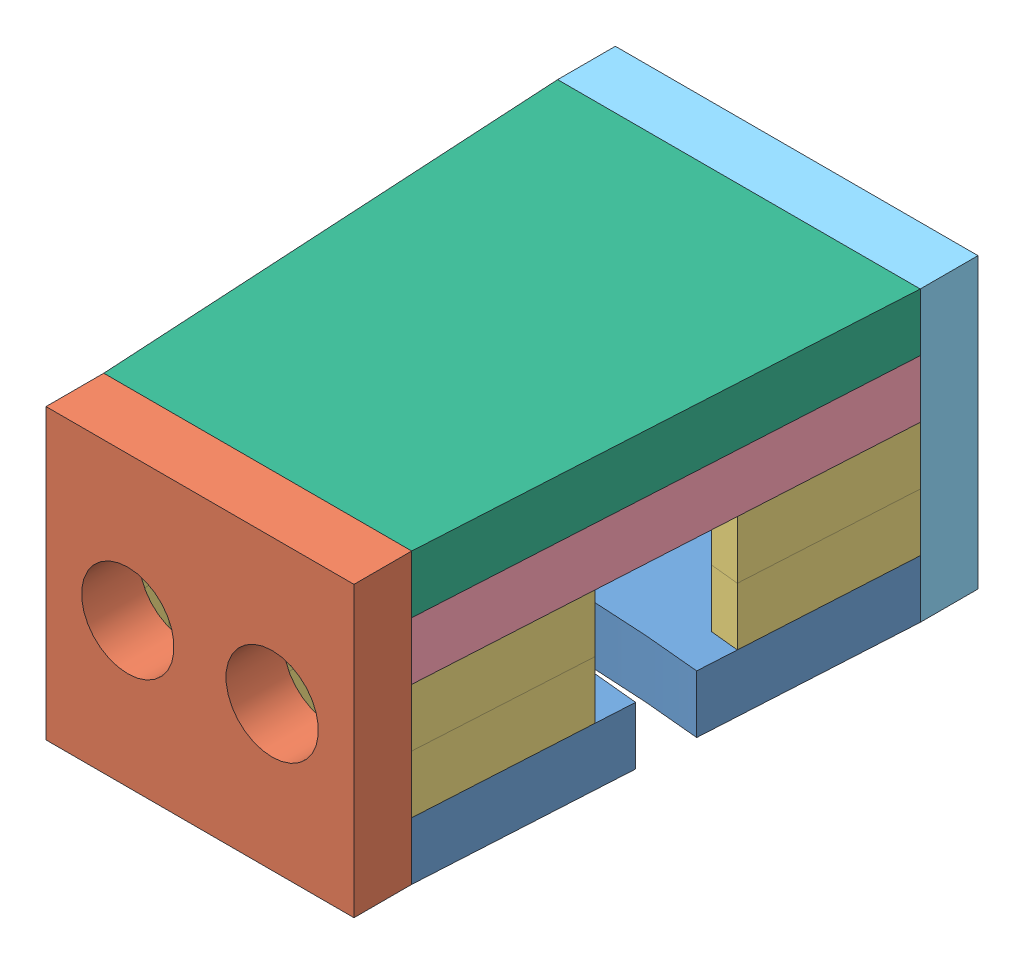
SolidWorks assembly housing, configuration Default. Lengths in mm.
Overall size (18.84 15 31).
7 component instances, 6 part files, 23 mates.
Components (placement in the parent):
- housing-bottom-1: housing-bottom [Default] at (19.3006 18.161 112.8173) size (18.84 3 25)
- housing-inside-1: housing-inside [Default] at (19.3006 25.661 48.3173) x (1 0 0) z (0 -1 0) size (16 3 15)
- housing-middle-bottom-1: housing-middle-bottom [Default] at (19.3006 21.161 112.8173) size (18.84 3 25)
- housing-middle-top-1: housing-middle-top [Default] at (19.3006 27.161 112.8173) size (18.84 3 25)
- housing-outside-1: housing-outside [Default] at (19.3002 25.661 20.3173) x (1 0 0) z (0 -1 0) size (18.84 3 15)
- housing-top-1: housing-top [Default] at (19.3006 30.161 112.8173) size (18.84 3 25)
- housing-middle-bottom-2: housing-middle-bottom [Default] at (19.3006 24.161 112.8173) size (18.84 3 25)
Mates (geometry in assembly coordinates):
- Coincident7: coincident anti-aligned: plane of housing-middle-top-1 through (19.3006 27.161 112.8173) normal (0 -1 0); plane of housing-middle-bottom-2 through (19.3006 27.161 112.8173) normal (0 1 0)
- Coincident8: coincident aligned: plane of housing-middle-top-1 through (19.3006 30.161 48.3173) normal (0 0 1); plane of housing-middle-bottom-2 through (19.3006 27.161 48.3173) normal (0 0 1)
- Coincident9: coincident aligned: plane of housing-middle-top-1 through (9.881 30.161 23.3173) normal (-0.998392 0 0.056693); plane of housing-middle-bottom-2 through (9.881 27.161 23.3173) normal (-0.998392 0 0.056693)
- Coincident10: coincident anti-aligned: plane of housing-middle-top-1 through (19.3006 30.161 112.8173) normal (0 1 0); plane of housing-top-1 through (19.3006 30.161 112.8173) normal (0 -1 0)
- Coincident11: coincident aligned: plane of housing-middle-top-1 through (19.3006 30.161 48.3173) normal (0 0 1); plane of housing-top-1 through (19.3006 33.161 48.3173) normal (0 0 1)
- Coincident13: coincident anti-aligned: plane of housing-inside-1 through (19.3006 25.661 48.3173) normal (0 0 -1); plane of housing-top-1 through (19.3006 33.161 48.3173) normal (0 0 1)
- Coincident14: coincident aligned: plane of housing-bottom-1 through (19.3006 18.161 112.8173) normal (0 -1 0); plane of housing-inside-1 through (11.3006 18.161 51.3173) normal (0 -1 0)
- Coincident16: coincident anti-aligned: plane of housing-outside-1 through (19.3002 25.661 23.3173) normal (0 0 1); plane of housing-top-1 through (9.881 33.161 23.3173) normal (0 0 -1)
- Coincident17: coincident aligned: plane of housing-bottom-1 through (19.3006 18.161 112.8173) normal (0 -1 0); plane of housing-outside-1 through (9.8802 18.161 23.3173) normal (0 -1 0)
- Coincident19: coincident anti-aligned: plane of housing-outside-1 through (19.3002 25.661 20.3173) normal (0 0 -1); plane of ? through (19.3002 25.661 20.3173) normal (0 0 1)
- Coincident20: coincident aligned: plane of housing-outside-1 through (9.8802 18.161 23.3173) normal (-1 0 0); plane of ? through (9.8802 18.161 20.3173) normal (-1 0 0)
- Coincident21: coincident aligned: plane of housing-outside-1 through (9.8802 33.161 23.3173) normal (0 1 0); plane of ? through (9.8802 33.161 20.3173) normal (0 1 0)
- Coincident22: coincident anti-aligned: plane of housing-inside-1 through (19.3006 25.661 51.3173) normal (0 0 1); plane of ? through (19.3006 25.661 51.3173) normal (0 0 -1)
- Coincident23: coincident aligned: plane of housing-inside-1 through (11.3006 33.161 51.3173) normal (0 1 0); plane of ? through (11.3006 33.161 54.3173) normal (0 1 0)
- Coincident24: coincident aligned: plane of housing-inside-1 through (27.3006 18.161 51.3173) normal (1 0 0); plane of ? through (27.3006 18.161 54.3173) normal (1 0 0)
- Coincident25: coincident anti-aligned: plane of housing-bottom-1 through (19.3006 21.161 112.8173) normal (0 1 0); plane of housing-middle-bottom-1 through (19.3006 21.161 112.8173) normal (0 -1 0)
- Coincident26: coincident aligned: plane of housing-bottom-1 through (9.881 21.161 23.3173) normal (0 0 -1); plane of housing-middle-bottom-1 through (9.881 24.161 23.3173) normal (0 0 -1)
- Coincident27: coincident aligned: plane of housing-bottom-1 through (9.881 21.161 23.3173) normal (-0.998392 0 0.056693); plane of housing-middle-bottom-1 through (9.881 24.161 23.3173) normal (-0.998392 0 0.056693)
- Coincident28: coincident anti-aligned: plane of housing-middle-bottom-1 through (19.3006 24.161 112.8173) normal (0 1 0); plane of housing-middle-bottom-2 through (19.3006 24.161 112.8173) normal (0 -1 0)
- Coincident29: coincident aligned: plane of housing-middle-bottom-1 through (9.881 24.161 23.3173) normal (-0.998392 0 0.056693); plane of housing-middle-bottom-2 through (9.881 27.161 23.3173) normal (-0.998392 0 0.056693)
- Coincident30: coincident aligned: plane of housing-middle-bottom-1 through (9.881 24.161 23.3173) normal (0 0 -1); plane of housing-middle-bottom-2 through (9.881 27.161 23.3173) normal (0 0 -1)
- Coincident31: coincident aligned: line of housing-inside-1 through (11.3006 33.161 48.3173) axis (0 -1 0); line of housing-middle-top-1 through (11.3006 30.161 48.3173) axis (0 -1 0)
- Coincident32: coincident anti-aligned: line of housing-middle-top-1 through (28.7202 30.161 23.3173) axis (0 -1 0); line of housing-outside-1 through (28.7202 18.161 23.3173) axis (0 1 0)
